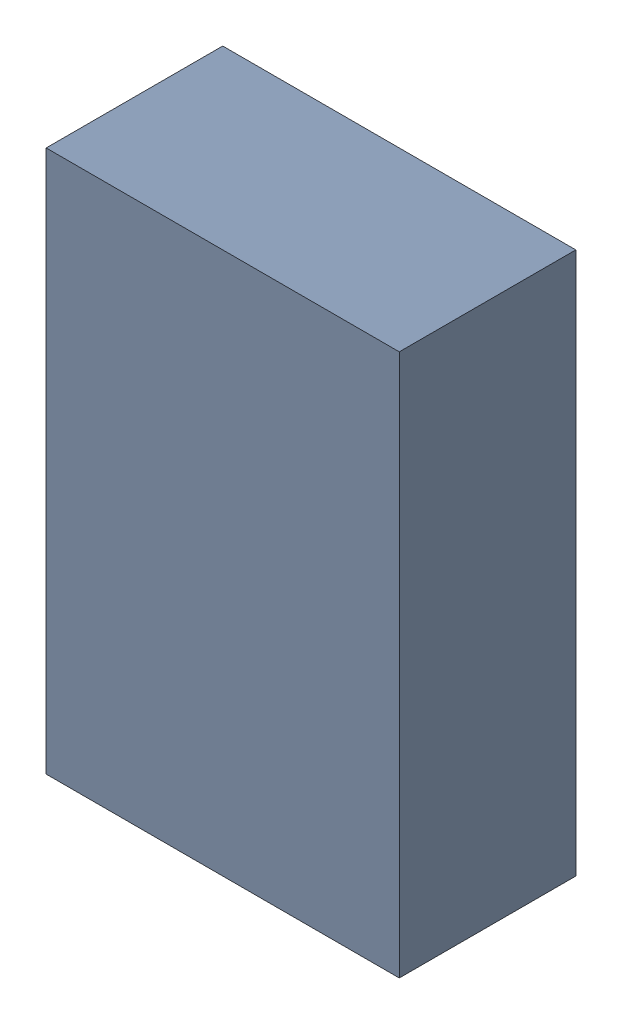
SolidWorks assembly R2, configuration Default. Lengths in mm.
Overall size (1.4 2.15 0.7).
2 component instances, 1 part files, 0 mates.
Components (placement in the parent):
- 959208120-1: 959208120 [Default] at (111.8912 75.852 0) size (1.4 2.15 0.7)
  - Extruded-20-1: Extruded-20 [Default] at origin size (1.4 2.15 0.7)
